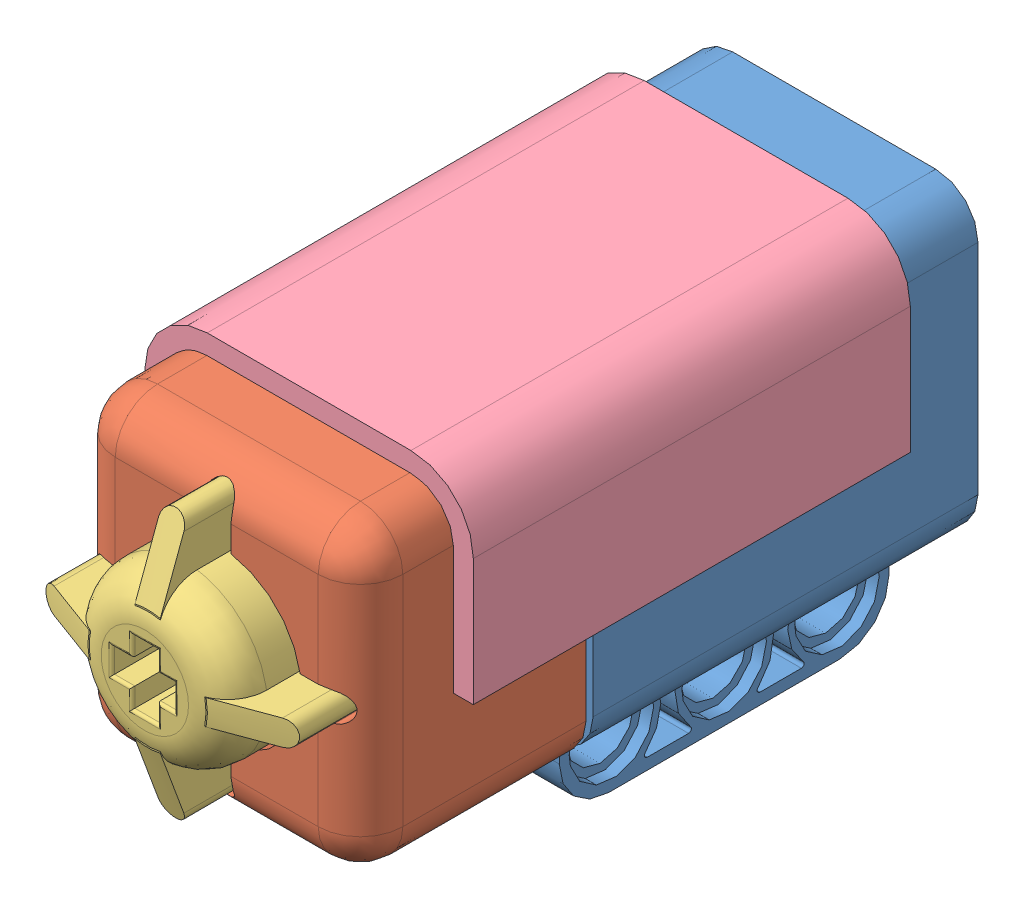
SolidWorks assembly Lego NXT - Touch sensor, configuration Default. Lengths in mm.
Overall size (23.3 31.4 48.8).
5 component instances, 5 part files, 12 mates.
Components (placement in the parent):
- Sensor NXT body-2: Sensor NXT body [Sound sensor body] at (10.1606 -4.4871 15.0506) size (20.4 30 27.8)
- Electric touch sensor NXT nose-1: Electric touch sensor NXT nose [Sound sensor body] at (10.1606 -4.4871 15.5506) size (20.4 21.5 16)
- Electric touch sensor NXT plunger-2: Electric touch sensor NXT plunger [Default] at (20.2606 6.3629 20.5506) size (18 19.1 10)
- Sensor NXT cover-1: Sensor NXT cover [Default] at (10.1606 5.0129 -21.9494) size (23.3 13.4 31)
- Sensor NXT body connector socket-2: Sensor NXT body connector socket [Default] at (27.0337 -2.8871 -28.2494) x (-1 0 0) z (0 0 -1) size (12.9 14.9 14.9)
Mates (geometry in assembly coordinates):
- Coincident1: coincident anti-aligned: plane of Sensor NXT body-2 through (30.5606 20.8 -0.4494) normal (0 0 1); plane of Electric touch sensor NXT nose-1 through (10.1606 17.0129 -0.4494) normal (0 0 -1)
- Coincident2: coincident anti-aligned: line of Sensor NXT body-2 through (13.1606 17.0129 -0.4494) axis (1 0 0); line of Electric touch sensor NXT nose-1 through (27.5606 17.0129 -0.4494) axis (-1 0 0)
- Coincident3: coincident aligned: line of Sensor NXT body-2 through (30.5606 4.0659 -0.4494) axis (0 1 0); line of Electric touch sensor NXT nose-1 through (30.5606 -1.4871 -0.4494) axis (0 1 0)
- Coincident4: coincident anti-aligned: plane of Electric touch sensor NXT nose-1 through (12.1606 7.2629 5.5506) normal (0 -1 0); plane of Electric touch sensor NXT plunger-2 through (16.9203 7.2629 20.3506) normal (0 1 0)
- Coincident5: coincident anti-aligned: plane of Electric touch sensor NXT nose-1 through (19.3606 15.0129 5.5506) normal (1 0 0); plane of Electric touch sensor NXT plunger-2 through (19.3606 9.7392 20.3506) normal (-1 0 0)
- LimitDistance1: limit distance = 5 mm aligned: plane of Electric touch sensor NXT nose-1 through (10.1606 17.0129 15.5506) normal (0 0 1); plane of Electric touch sensor NXT plunger-2 through (20.2606 6.3629 20.5506) normal (0 0 1)
- Coincident8: coincident anti-aligned: plane of Sensor NXT body-2 through (10.1606 -4.4871 -28.2494) normal (-1 0 0); plane of Sensor NXT cover-1 through (10.1606 5.0129 9.0506) normal (1 0 0)
- Coincident9: coincident anti-aligned: plane of Sensor NXT body-2 through (10.1606 17.0129 -28.2494) normal (0 1 0); plane of Sensor NXT cover-1 through (13.1856 17.0129 9.0506) normal (0 -1 0)
- Coincident10: coincident aligned: plane of Sensor NXT cover-1 through (13.1856 13.9879 9.0506) normal (0 0 1); plane of Sensor NXT body-2 through (10.1606 -4.4871 9.0506) normal (0 0 1)
- Coincident11: coincident anti-aligned: plane of Sensor NXT body-2 through (27.1337 12.0129 -8.2494) normal (0 -1 0); plane of Sensor NXT body connector socket-2 through (27.0337 12.0129 -13.3494) normal (0 1 0)
- Coincident12: coincident anti-aligned: plane of Sensor NXT body-2 through (14.1337 -2.9871 -8.2494) normal (1 0 0); plane of Sensor NXT body connector socket-2 through (14.1337 -2.8871 -13.3494) normal (-1 0 0)
- Coincident13: coincident aligned: plane of Sensor NXT body-2 through (10.1606 17.0129 -28.2494) normal (0 0 -1); plane of Sensor NXT body connector socket-2 through (27.0337 12.0129 -28.2494) normal (0 0 -1)
